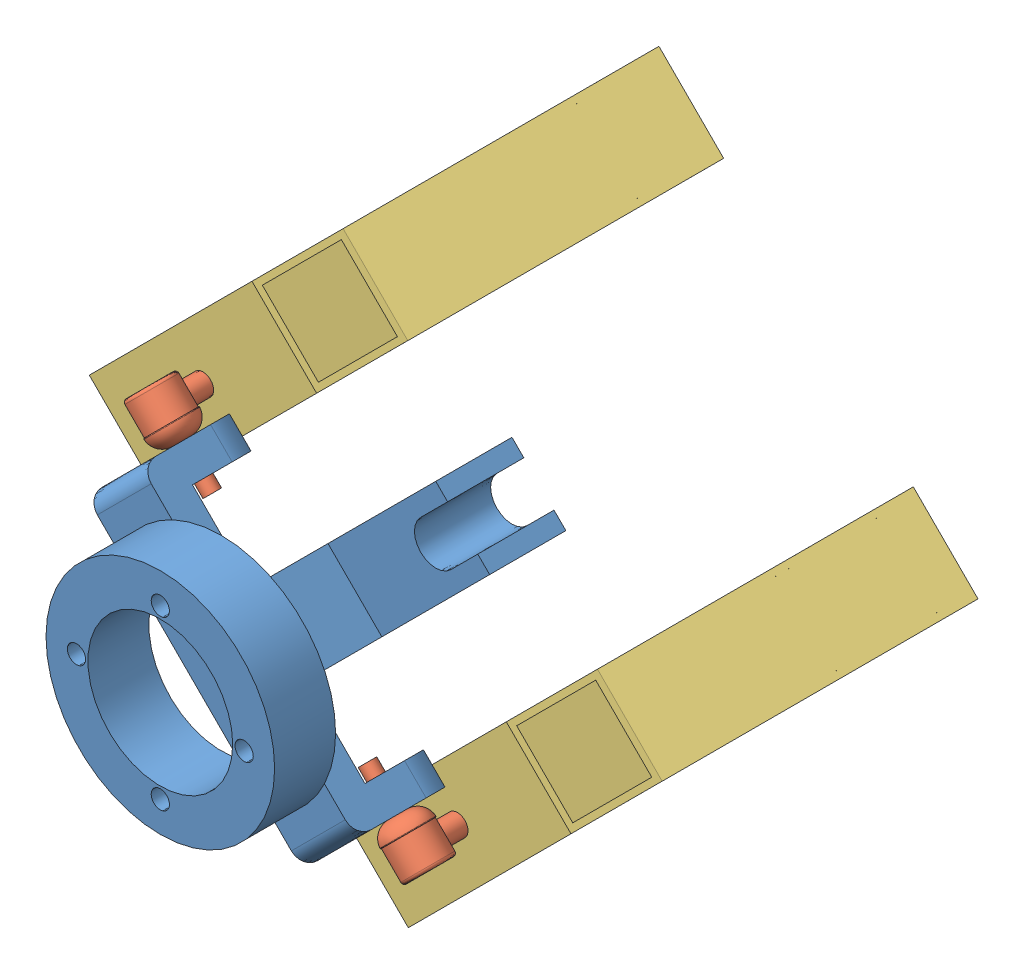
SolidWorks assembly Złożenie prototyp, configuration Domyślna. Lengths in mm.
Overall size (351.51 351.51 361.93).
5 component instances, 3 part files, 12 mates.
Components (placement in the parent):
- zwrotnica1-1: zwrotnica1 [Domyślna] at (112.4404 -40.3404 234.017) size (194.45 194.45 160)
- Sworzeń-1: Sworzeń [Domyślna] at (204.3642 -132.2643 189.017) x (-0.003063 -0.003063 -0.999991) z (-0.707107 0.707107 0) size (76.99 29.97 58)
- Sworzeń-2: Sworzeń [Domyślna] at (20.5165 51.5835 189.017) x (-0.003063 -0.003063 -0.999991) z (0.707107 -0.707107 0) size (76.99 29.97 58)
- Wahacz-1: Wahacz [Domyślna] at (28.8287 42.9251 132.5175) x (-0.003063 -0.003063 -0.999991) z (0.7071 0.7071 -0.004332) size (250 60.03 200)
- Wahacz-2: Wahacz [Domyślna] at (195.7059 -123.9521 132.5175) x (-0.003063 -0.003063 -0.999991) z (0.7071 0.7071 -0.004332) size (250 60.03 200)
Mates (geometry in assembly coordinates):
- Koncentryczne1: concentric aligned: cylinder of zwrotnica1-1 through (200.8287 -128.7288 189.017) axis (-0.707107 0.707107 0) radius 7; cylinder of Sworzeń-2 through (61.5287 10.5713 189.017) axis (-0.707107 0.707107 0) radius 5
- Wspólnie1: coincident anti-aligned: plane of zwrotnica1-1 through (41.7297 30.3703 234.017) normal (-0.707107 0.707107 0); circle of Sworzeń-2
- Koncentryczne2: concentric anti-aligned: cylinder of zwrotnica1-1 through (200.8287 -128.7288 189.017) axis (-0.707107 0.707107 0) radius 7; cylinder of Sworzeń-1 through (163.352 -91.2521 189.017) axis (0.707107 -0.707107 0) radius 5
- Koncentryczne4: concentric aligned: circle of zwrotnica1-1; circle of Sworzeń-1
- Wspólnie2: coincident anti-aligned: plane of zwrotnica1-1 through (183.151 -111.0511 234.017) normal (0.707107 -0.707107 0); circle of Sworzeń-1
- Koncentryczne5: concentric aligned: cylinder of Sworzeń-1 through (195.689 -123.9689 127.0176) axis (0.003063 0.003063 0.999991) radius 5; cylinder of Wahacz-2 through (195.7212 -123.9368 137.5175) axis (0.003063 0.003063 0.999991) radius 5
- Wspólnie3: coincident anti-aligned: plane of Sworzeń-1 through (195.7978 -123.8602 162.5172) normal (-0.003063 -0.003063 -0.999991); plane of Wahacz-2 through (270.0435 -92.0409 162.1923) normal (0.003063 0.003063 0.999991)
- Koncentryczne6: concentric aligned: cylinder of Sworzeń-2 through (28.8118 42.9083 127.0176) axis (0.003063 0.003063 0.999991) radius 5; cylinder of Wahacz-1 through (28.844 42.9404 137.5175) axis (0.003063 0.003063 0.999991) radius 5
- Wspólnie4: coincident anti-aligned: plane of Sworzeń-2 through (28.9206 43.017 162.5172) normal (-0.003063 -0.003063 -0.999991); plane of Wahacz-1 through (103.1663 74.8363 162.1923) normal (0.003063 0.003063 0.999991)
- Równolegle1: parallel aligned: plane of zwrotnica1-1 through (55.8718 16.2281 234.017) normal (0.707107 -0.707107 0); plane of Wahacz-1 through (103.1663 74.8363 162.1923) normal (0.707107 -0.707107 0)
- Równolegle2: parallel aligned: plane of zwrotnica1-1 through (169.0089 -96.909 234.017) normal (-0.707107 0.707107 0); plane of Wahacz-2 through (227.6171 -49.6145 162.1923) normal (-0.707107 0.707107 0)
- Wspólnie7: coincident aligned: plane of Wahacz-1 through (28.1547 42.2512 -87.4804) normal (-0.003063 -0.003063 -0.999991); plane of Wahacz-2 through (195.0319 -124.626 -87.4804) normal (-0.003063 -0.003063 -0.999991)
